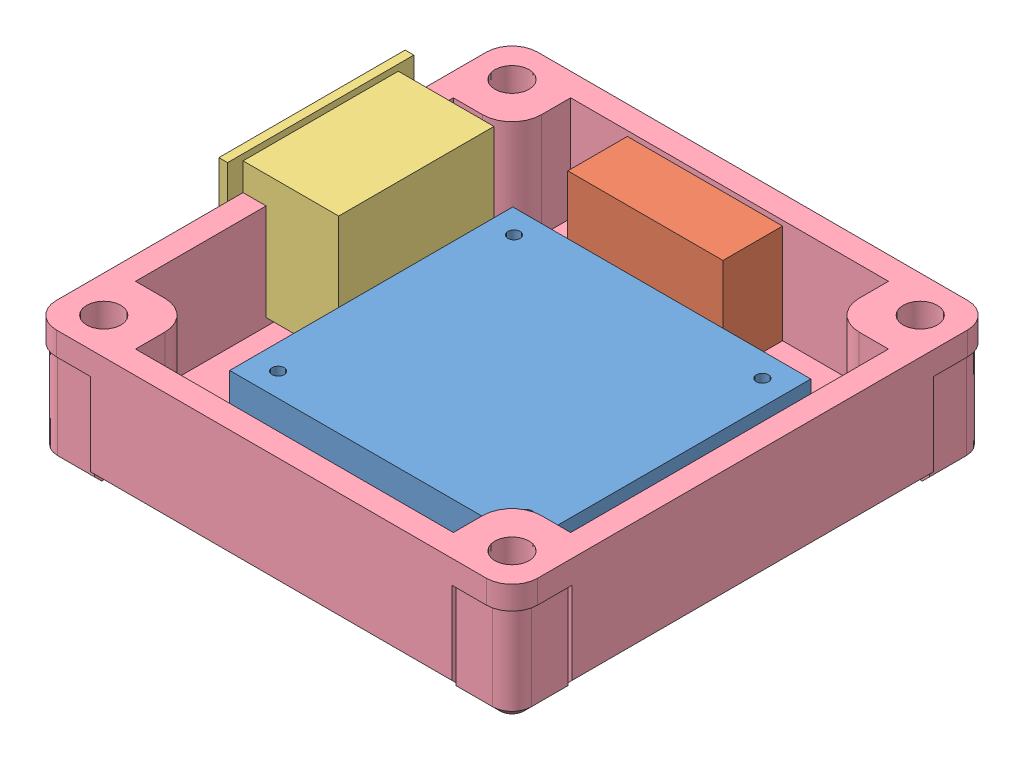
SolidWorks assembly Assem2, configuration Default. Lengths in mm.
Overall size (100.2 31.32 98.42).
4 component instances, 4 part files, 6 mates.
Components (placement in the parent):
- CHB50-1: CHB50 [Default] at (-67.8403 55.6803 52.2269) x (0.000146 0 1) z (-1 0 0.000146) size (57.91 12.7 60.96)
- LDD-L-1: LDD-L [Default] at (-75.6025 65.8403 18.8773) x (0 1 0) z (-1 0 0) size (20.32 12.19 31.75)
- 1470G1-1: 1470G1 [Default] at (-119.7837 69.9678 41.1023) x (0 0 1) z (-1 0 0) size (38.1 27.94 21.34)
- 69945K317_IMPACT-CORROSION-RESISTANT WASHDOWN ENCLOSURE-1: 69945K317_IMPACT-CORROSION-RESISTANT WASHDOWN ENCLOSURE [69945K317] at (-70.5712 52.6178 51.1853) x (1 0 0) z (0 1 0) size (98.42 98.42 24.42)
Mates (geometry in assembly coordinates):
- Coincident9: coincident anti-aligned: plane of CHB50-1 through (-67.8403 55.6803 52.2269) normal (0 -1 0); plane of 69945K317_IMPACT-CORROSION-RESISTANT WASHDOWN ENCLOSURE-1 through (-109.0712 55.6803 12.6853) normal (0 1 0)
- Coincident10: coincident anti-aligned: plane of 1470G1-1 through (-119.7837 69.9678 41.1023) normal (1 0 0); plane of 69945K317_IMPACT-CORROSION-RESISTANT WASHDOWN ENCLOSURE-1 through (-119.7837 77.0428 1.9728) normal (-1 0 0)
- Coincident12: coincident anti-aligned: plane of LDD-L-1 through (-59.7275 55.6803 6.6853) normal (0 -1 0); plane of 69945K317_IMPACT-CORROSION-RESISTANT WASHDOWN ENCLOSURE-1 through (-109.0712 55.6803 12.6853) normal (0 1 0)
- Coincident13: coincident anti-aligned: plane of LDD-L-1 through (-75.6025 65.8403 6.6853) normal (0 0 -1); plane of 69945K317_IMPACT-CORROSION-RESISTANT WASHDOWN ENCLOSURE-1 through (-38.0712 55.6803 6.6853) normal (0 0 1)
- Coincident14: coincident anti-aligned: plane of 1470G1-1 through (-100.2257 82.6678 25.2273) normal (0 0 -1); plane of 69945K317_IMPACT-CORROSION-RESISTANT WASHDOWN ENCLOSURE-1 through (-107.0837 82.6678 25.2273) normal (0 0 1)
- Coincident15: coincident anti-aligned: plane of 1470G1-1 through (-100.2257 57.2678 25.2273) normal (0 -1 0); plane of 69945K317_IMPACT-CORROSION-RESISTANT WASHDOWN ENCLOSURE-1 through (-107.0837 57.2678 25.2273) normal (0 1 0)
